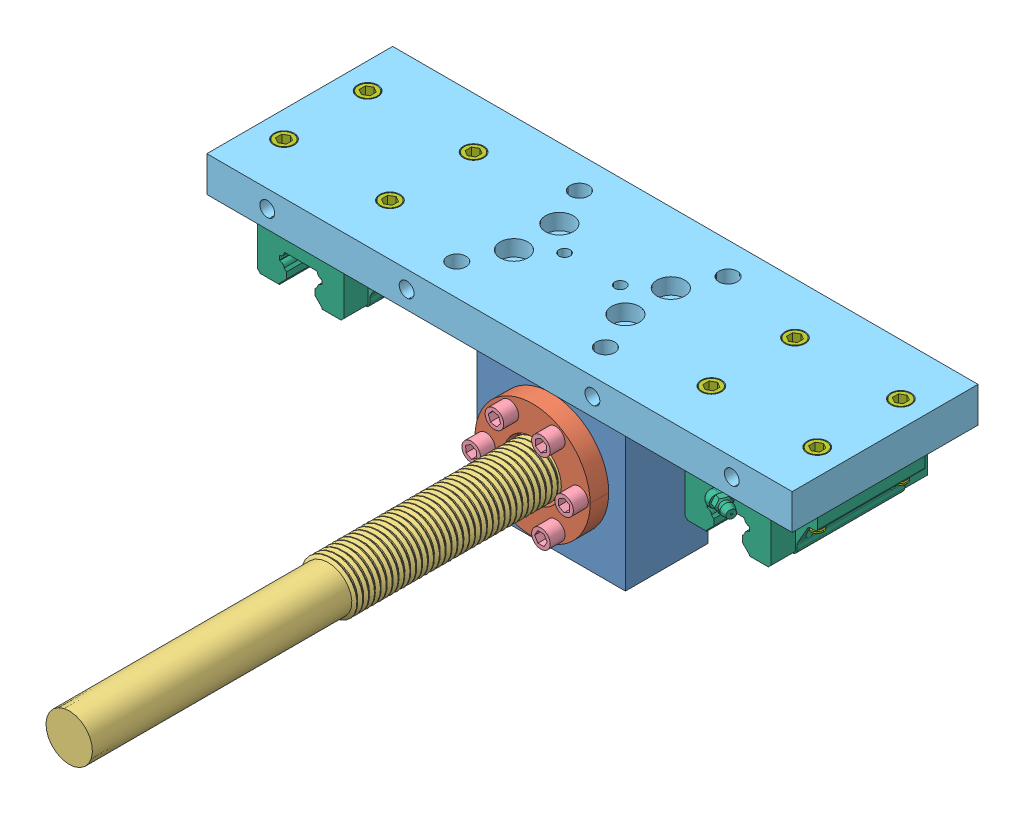
SolidWorks assembly Montagem_castanha, configuration Valor predeterminado. Lengths in mm.
Overall size (315 119.02 380).
21 component instances, 7 part files, 19 mates.
Components (placement in the parent):
- Bloco_transmissão-1: Bloco_transmissão [Valor predeterminado] at (-2.417 -10.5029 104.888) size (80 100 44.45)
- _BN25x5RNOWPRn_4-1: _BN25x5RNOWPRn_4 [Default] at (-2.417 -10.5029 137.113) x (0 0 -1) z (-1 0 0) size (44.5 62 62)
- _BN25x5R90_90G5_AA_0_0NOWPR_s_6-1: _BN25x5R90_90G5_AA_0_0NOWPR_s_6 [Default] at (-2.417 -10.5029 101.4546) x (0 0 -1) z (0.976935 0.213539 0) size (380 32.86 28.46)
- Allen_M6x40-1: Allen_M6x40 [Valor predeterminado] at (10.083 -32.1535 97.113) x (0.024122 -0.999709 0) z (0 0 1) size (10 10 48)
- Allen_M6x40-2: Allen_M6x40 [Valor predeterminado] at (22.583 -10.5029 97.113) size (10 10 48)
- Allen_M6x40-3: Allen_M6x40 [Valor predeterminado] at (-14.917 -32.1535 97.113) x (-0.548041 -0.836452 0) z (0 0 1) size (10 10 48)
- Allen_M6x40-4: Allen_M6x40 [Valor predeterminado] at (-27.417 -10.5029 97.113) x (0.552358 -0.833607 0) z (0 0 1) size (10 10 48)
- Allen_M6x40-5: Allen_M6x40 [Valor predeterminado] at (10.083 11.1477 97.113) x (0.490482 -0.871452 0) z (0 0 1) size (10 10 48)
- Allen_M6x40-6: Allen_M6x40 [Valor predeterminado] at (-14.917 11.1477 97.113) x (0.940825 0.338892 0) z (0 0 1) size (10 10 48)
- Montagem_plataforma_patins-1: Montagem_plataforma_patins [Valor predeterminado] at (33.4251 62.5499 -44.6676) size (315 49.52 108.05)
  - Plataforma-1: Plataforma [Valor predeterminado] at (-35.8421 -14.4528 149.5555) size (315 19.02 100)
  - KRH25-FL-N-Z0-1: KRH25-FL-N-Z0 [Valor predeterminado] at (79.1579 -44.9528 191.5555) x (0 0 -1) z (0 1 0) size (96 70 30.5)
  - KRH25-FL-N-Z0-2: KRH25-FL-N-Z0 [Valor predeterminado] at (-150.8421 -44.9528 107.5055) x (0 0 1) z (0 1 0) size (96 70 30.5)
  - Allen_M6x30-1: Allen_M6x30 [Valor predeterminado] at (107.6579 -33.4328 127.0555) x (1 0 0) z (0 1 0) size (10 10 38)
  - Allen_M6x30-2: Allen_M6x30 [Valor predeterminado] at (107.6579 -33.4328 172.0555) x (1 0 0) z (0 1 0) size (10 10 38)
  - Allen_M6x30-3: Allen_M6x30 [Valor predeterminado] at (-179.3421 -33.4328 172.0055) x (1 0 0) z (0 1 0) size (10 10 38)
  - Allen_M6x30-4: Allen_M6x30 [Valor predeterminado] at (-122.3421 -33.4328 172.0055) x (1 0 0) z (0 1 0) size (10 10 38)
  - Allen_M6x30-5: Allen_M6x30 [Valor predeterminado] at (-179.3421 -33.4328 127.0055) x (1 0 0) z (0 1 0) size (10 10 38)
  - Allen_M6x30-6: Allen_M6x30 [Valor predeterminado] at (-122.3421 -33.4328 127.0055) x (1 0 0) z (0 1 0) size (10 10 38)
  - Allen_M6x30-7: Allen_M6x30 [Valor predeterminado] at (50.6579 -33.4328 127.0555) x (1 0 0) z (0 1 0) size (10 10 38)
  - Allen_M6x30-8: Allen_M6x30 [Valor predeterminado] at (50.6579 -33.4328 172.0555) x (1 0 0) z (0 1 0) size (10 10 38)
Mates (geometry in assembly coordinates):
- Coincidente4: coincident anti-aligned: plane of Bloco_transmissão-1 through (-2.417 -10.5029 127.113) normal (0 0 1); plane of _BN25x5RNOWPRn_4-1 through (-2.417 -10.5029 127.113) normal (0 0 -1)
- Coincidente5: coincident anti-aligned: circle of Bloco_transmissão-1; cylinder of _BN25x5RNOWPRn_4-1 through (10.083 -32.1535 127.113) axis (0 0 -1) radius 3.3
- Concêntrico7: concentric anti-aligned: circle of Bloco_transmissão-1; cylinder of _BN25x5RNOWPRn_4-1 through (-14.917 -32.1535 127.113) axis (0 0 -1) radius 3.3
- Concêntrico8: concentric aligned: cylinder of _BN25x5RNOWPRn_4-1 through (-2.417 -10.5029 92.613) axis (0 0 1) radius 12.5; cylinder of _BN25x5R90_90G5_AA_0_0NOWPR_s_6-1 through (-2.417 -10.5029 56.4546) axis (0 0 1) radius 12.5
- Concêntrico9: concentric aligned: cylinder of _BN25x5RNOWPRn_4-1 through (-14.917 11.1477 127.113) axis (0 0 -1) radius 3.3; cylinder of Allen_M6x45-6 through (-14.917 11.1477 145.113) axis (0 0 -1) radius 5
- Concêntrico10: concentric aligned: cylinder of _BN25x5RNOWPRn_4-1 through (10.083 11.1477 127.113) axis (0 0 -1) radius 3.3; cylinder of Allen_M6x45-5 through (10.083 11.1477 145.113) axis (0 0 -1) radius 5
- Concêntrico11: concentric aligned: cylinder of _BN25x5RNOWPRn_4-1 through (-27.417 -10.5029 127.113) axis (0 0 -1) radius 3.3; cylinder of Allen_M6x45-4 through (-27.417 -10.5029 145.113) axis (0 0 -1) radius 5
- Concêntrico14: concentric aligned: cylinder of _BN25x5RNOWPRn_4-1 through (-14.917 -32.1535 127.113) axis (0 0 -1) radius 3.3; cylinder of Allen_M6x45-3 through (-14.917 -32.1535 145.113) axis (0 0 -1) radius 5
- Concêntrico15: concentric aligned: cylinder of _BN25x5RNOWPRn_4-1 through (10.083 -32.1535 127.113) axis (0 0 -1) radius 3.3; cylinder of Allen_M6x45-1 through (10.083 -32.1535 145.113) axis (0 0 -1) radius 5
- Concêntrico16: concentric aligned: cylinder of _BN25x5RNOWPRn_4-1 through (22.583 -10.5029 127.113) axis (0 0 -1) radius 3.3; cylinder of Allen_M6x45-2 through (22.583 -10.5029 145.113) axis (0 0 -1) radius 5
- Coincidente7: coincident anti-aligned: plane of _BN25x5RNOWPRn_4-1 through (-2.417 -29.5029 137.113) normal (0 0 1); plane of Allen_M6x45-5 through (10.083 11.1477 137.113) normal (0 0 -1)
- Coincidente8: coincident anti-aligned: plane of _BN25x5RNOWPRn_4-1 through (-2.417 -29.5029 137.113) normal (0 0 1); plane of Allen_M6x45-2 through (22.583 -10.5029 137.113) normal (0 0 -1)
- Coincidente9: coincident anti-aligned: plane of _BN25x5RNOWPRn_4-1 through (-2.417 -29.5029 137.113) normal (0 0 1); plane of Allen_M6x45-1 through (10.083 -32.1535 137.113) normal (0 0 -1)
- Coincidente10: coincident anti-aligned: plane of _BN25x5RNOWPRn_4-1 through (-2.417 -29.5029 137.113) normal (0 0 1); plane of Allen_M6x45-6 through (-14.917 11.1477 137.113) normal (0 0 -1)
- Coincidente11: coincident anti-aligned: plane of _BN25x5RNOWPRn_4-1 through (-2.417 -29.5029 137.113) normal (0 0 1); plane of Allen_M6x45-4 through (-27.417 -10.5029 137.113) normal (0 0 -1)
- Coincidente12: coincident aligned: plane of _BN25x5RNOWPRn_4-1 through (-2.417 -29.5029 137.113) normal (0 0 1); circle of Allen_M6x45-3
- Concêntrico17: concentric aligned: circle of Bloco_transmissão-1; cylinder of Montagem_plataforma_patins-1/Plataforma-1 through (-32.417 67.1171 117.113) axis (0 1 0) radius 7.5
- Concêntrico18: concentric aligned: circle of Bloco_transmissão-1; circle of Montagem_plataforma_patins-1/Plataforma-1
- Coincidente14: coincident anti-aligned: plane of Bloco_transmissão-1 through (-42.417 48.0971 127.113) normal (0 1 0); plane of Montagem_plataforma_patins-1/Plataforma-1 through (-2.417 48.0971 104.888) normal (0 -1 0)
